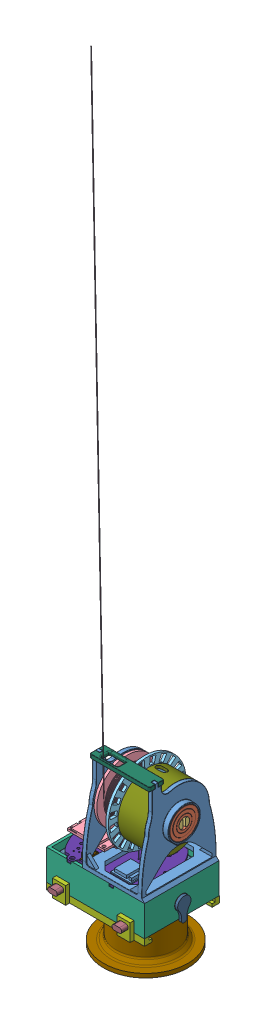
SolidWorks assembly Assembly, configuration Default. Lengths in mm.
Overall size (85.35 593.17 76.41).
29 component instances, 23 part files, 50 mates.
Components (placement in the parent):
- Housing-1: Housing [Default] at (10.1517 -3.3403 -3.0876) size (55.02 71.75 56)
- 608 bearing-1: 608 bearing [Default] at (31.6517 33.1597 24.9124) size (7 22 22)
- 608 bearing-2: 608 bearing [Default] at (-14.3483 33.1597 24.9124) size (7 22 22)
- Axel-1: Axel [Default] at (-5.3483 33.1597 24.9124) size (53 5.9 7.9)
- Spindle Encoder-1: Spindle Encoder [Default] at (-9.8483 33.1597 24.9124) x (0 -0.002146 0.999998) z (1 0 0) size (49.41 522.62 53)
- Spindle Housing-1: Spindle Housing [Default] at (7.1517 33.1597 24.9124) x (0 -0.924225 -0.381849) z (-1 0 0) size (58.5 58.5 53)
- Battery compartment-1: Battery compartment [Default] at (-4.0483 -29.3403 24.9124) x (0 0 1) z (-1 0 0) size (56 23 74)
- Compartment Bottom-1: Compartment Bottom [Default] at (-4.0483 -29.6403 24.6124) x (0 0 1) z (-1 0 0) size (62.6 12.9 74)
- Pillar-1: Pillar [Default] at (5.7517 -29.9403 24.6124) x (0 0 1) z (1 0 0) size (49.4 4 44.7)
- Pillar Base-1: Pillar Base [Default] at (5.7517 -57.3403 24.6124) x (0 0 -1) z (1 0 0) size (63.5 28.4 63.5)
- Pillar Lock-2: Pillar Lock [Default] at (30.5517 -19.3403 24.9124) x (0 0 -1) z (1 0 0) size (10 17.3 2)
- Pillar Lock Flange-2: Pillar Lock Flange [Default] at (30.9517 -19.3403 24.9124) x (0 -0.052142 0.99864) z (1 0 0) size (14 14 4.2)
- Piller Balance-1: Piller Balance [Default] at (-4.0483 -29.6403 24.6124) x (0 0 1) z (-1 0 0) size (51.4 4.63 48.65)
- Dowel-1: Dowel [Default] at (20.2517 -25.3403 50.3124) x (0 0 1) z (-1 0 0) size (10.6 3.7 7)
- Dowel-2: Dowel [Default] at (-28.3483 -25.3403 -1.0876) x (0 0 -1) z (1 0 0) size (10.6 3.7 7)
- Dowel-3: Dowel [Default] at (20.2517 -25.3403 -1.0876) x (0 0 -1) z (1 0 0) size (10.6 3.7 7)
- Dowel-4: Dowel [Default] at (-28.3483 -25.3403 50.3124) x (0 0 1) z (-1 0 0) size (10.6 3.7 7)
- Battery Case-1: Battery Case [Default] at (-4.0483 -27.3103 24.9124) x (0 0 -1) z (1 0 0) size (50 18 66)
- String Guard-1: String Guard [Default] at (-10.8483 62.4097 42.6624) size (45 3 11)
- Spring Mount Thin-1: Spring Mount Thin [Default] at (8.1517 33.1597 24.9124) size (20 46 46)
- PCB_Final-1: PCB_Final [Default] at (-8.0878 -10.7225 17.4115) x (0 0 -1) z (0 1 0) size (56.29 65.69 17.53)
  - JDL_PCB_From_Eagle-1: JDL_PCB_From_Eagle [Default] at (-7.6824 -3.0353 2.7693) size (56.29 65.69 1.61)
  - JDL_95C06F3GWT_TactSwitch-1: JDL_95C06F3GWT_TactSwitch [Default] at (-26.1821 9.2553 4.3822) x (-1 0 0) z (0 1 0) size (9.93 10.41 6.35)
  - JDL_95C06F3GWT_TactSwitch-2: JDL_95C06F3GWT_TactSwitch [Default] at (11.4099 9.2553 4.3822) x (-1 0 0) z (0 1 0) size (9.93 10.41 6.35)
  - JDL_RFDuino-1: JDL_RFDuino [Default] at (-20.5361 -15.9626 4.3822) x (1 0 0) z (0 -1 0) size (15.24 2.97 15.24)
  - JDL_JST_Female-1: JDL_JST_Female [Default] at (-11.5107 14.455 -0.5307) x (0 -1 0) z (1 0 0) size (7.9 5.5 7.6)
  - JDL_Inductor-1: JDL_Inductor [Default] at (-5.5489 20.3469 4.3822) x (1 0 0) z (0 -1 0) size (5.3 4.5 5.8)
  - OLED_NoOffset-1: OLED_NoOffset [Default] at (-7.7274 16.7735 9.2082) x (1 0 0) z (0 -1 0) size (28 12 28)
- Emitter_Detector-1: Emitter_Detector [Default] at (2.3717 -5.3603 24.9218) x (0 0 -1) z (1 0 0) size (7.82 15.5 11.48)
Mates (geometry in assembly coordinates):
- Concentric1: concentric anti-aligned: cylinder of Housing-1 through (-13.8483 33.1597 24.9124) axis (1 0 0) radius 11.15; cylinder of 608 bearing-1 through (31.1088 33.1597 24.9124) axis (-1 0 0) radius 11
- Coincident1: coincident aligned: plane of Housing-1 through (28.1517 -1.3403 52.9124) normal (-1 0 0); plane of 608 bearing-1 through (28.1517 28.9557 24.9124) normal (-1 0 0)
- Concentric2: concentric anti-aligned: cylinder of Housing-1 through (-13.8483 33.1597 24.9124) axis (1 0 0) radius 11.15; cylinder of 608 bearing-2 through (-14.8912 33.1597 24.9124) axis (-1 0 0) radius 11
- Coincident2: coincident aligned: plane of Housing-1 through (-10.8483 -1.3403 52.9124) normal (1 0 0); plane of 608 bearing-2 through (-10.8483 28.9557 24.9124) normal (1 0 0)
- Coincident3: coincident aligned: plane of 608 bearing-1 through (35.1517 28.9557 24.9124) normal (1 0 0); plane of Axel-1 through (35.1517 33.1597 24.9124) normal (1 0 0)
- Coincident5: coincident anti-aligned: plane of Spindle Encoder-1 through (5.1517 20.5273 24.8853) normal (1 0 0); plane of Spindle Housing-1 through (5.1517 33.1597 24.9124) normal (-1 0 0)
- Coincident43: coincident aligned: plane of Battery compartment-1 through (33.1517 -16.3403 52.9124) normal (1 0 0); plane of Compartment Bottom-1 through (33.1517 -31.9403 52.6124) normal (1 0 0)
- Parallel2: parallel anti-aligned: plane of Compartment Bottom-1 through (-15.2483 -61.6629 24.6124) normal (1 0 0); plane of Pillar-1 through (-14.2483 -31.9403 39.1069) normal (-1 0 0)
- Concentric18: concentric aligned: cylinder of Compartment Bottom-1 through (5.7517 -31.9403 24.6124) axis (0 1 0) radius 25; cylinder of Pillar-1 through (5.7517 -31.9403 24.6124) axis (0 1 0) radius 24.7
- Coincident54: coincident anti-aligned: plane of Pillar-1 through (5.7517 -31.9403 24.6124) normal (0 -1 0); plane of Pillar Base-1 through (5.7517 -31.9403 37.3124) normal (0 1 0)
- Concentric20: concentric aligned: cylinder of Pillar-1 through (5.7517 -31.9403 24.6124) axis (0 1 0) radius 24.7; cylinder of Pillar Base-1 through (5.7517 -31.9403 24.6124) axis (0 1 0) radius 22.2
- Coincident56: coincident anti-aligned: plane of Battery compartment-1 through (-40.8483 -29.3403 52.9124) normal (0 -1 0); plane of Compartment Bottom-1 through (5.7517 -29.3403 24.6124) normal (0 1 0)
- Concentric21: concentric anti-aligned: circle of 608 bearing-1; circle of Axel-1
- Concentric22: concentric anti-aligned: circle of Axel-1; circle of Spindle Housing-1
- Coincident67: coincident anti-aligned: plane of Compartment Bottom-1 through (5.7517 -31.9403 24.6124) normal (0 1 0); plane of Pillar-1 through (5.7517 -31.9403 24.6124) normal (0 -1 0)
- Coincident73: coincident anti-aligned: plane of Compartment Bottom-1 through (-17.2483 -31.9403 38.7546) normal (-1 0 0); plane of Piller Balance-1 through (-17.2483 -29.3103 38.7546) normal (1 0 0)
- Distance13: distance = 0.03 mm anti-aligned: plane of Piller Balance-1 through (5.7517 -29.3103 24.6124) normal (0 -1 0); plane of Compartment Bottom-1 through (5.7517 -29.3403 24.6124) normal (0 1 0)
- Concentric23: concentric anti-aligned: cylinder of Compartment Bottom-1 through (5.7517 -31.9403 24.6124) axis (0 1 0) radius 25; cylinder of Piller Balance-1 through (5.7517 -29.3103 24.6124) axis (0 -1 0) radius 27
- Coincident74: coincident anti-aligned: plane of Compartment Bottom-1 through (-33.3483 -21.3403 55.9124) normal (0 0 1); plane of Dowel-4 through (-24.8483 -23.4903 55.9124) normal (0 0 -1)
- Concentric24: concentric aligned: cylinder of Battery compartment-1 through (-28.3483 -25.3403 66.9124) axis (0 0 -1) radius 2.65; cylinder of Dowel-4 through (-28.3483 -25.3403 55.9124) axis (0 0 -1) radius 2.35
- Coincident75: coincident anti-aligned: plane of Compartment Bottom-1 through (15.2517 -21.3403 55.9124) normal (0 0 1); plane of Dowel-1 through (23.7517 -23.4903 55.9124) normal (0 0 -1)
- Concentric25: concentric aligned: cylinder of Battery compartment-1 through (20.2517 -25.3403 66.9124) axis (0 0 -1) radius 2.65; cylinder of Dowel-1 through (20.2517 -25.3403 55.9124) axis (0 0 -1) radius 2.35
- Coincident76: coincident anti-aligned: plane of Compartment Bottom-1 through (-33.3483 -21.3403 -6.6876) normal (0 0 -1); plane of Dowel-2 through (-31.8483 -23.4903 -6.6876) normal (0 0 1)
- Concentric26: concentric anti-aligned: cylinder of Battery compartment-1 through (-28.3483 -25.3403 66.9124) axis (0 0 -1) radius 2.65; cylinder of Dowel-2 through (-28.3483 -25.3403 -6.6876) axis (0 0 1) radius 2.35
- Coincident77: coincident anti-aligned: plane of Compartment Bottom-1 through (15.2517 -21.3403 -6.6876) normal (0 0 -1); plane of Dowel-3 through (16.7517 -23.4903 -6.6876) normal (0 0 1)
- Concentric27: concentric anti-aligned: cylinder of Battery compartment-1 through (20.2517 -25.3403 66.9124) axis (0 0 -1) radius 2.65; cylinder of Dowel-3 through (20.2517 -25.3403 -6.6876) axis (0 0 1) radius 2.35
- Coincident100: coincident anti-aligned: plane of Piller Balance-1 through (5.7517 -27.3103 24.6124) normal (0 1 0); plane of Battery Case-1 through (-37.0483 -27.3103 -0.0876) normal (0 -1 0)
- Distance24: distance = 1 mm anti-aligned: plane of Battery Case-1 through (-4.0483 -9.3103 -0.0876) normal (0 0 -1); plane of Battery compartment-1 through (31.1517 -16.3403 -1.0876) normal (0 0 1)
- Coincident102: coincident anti-aligned: plane of Battery compartment-1 through (-4.0483 -16.3403 52.9124) normal (0 0 1); plane of Compartment Bottom-1 through (-33.3483 -21.3403 52.9124) normal (0 0 -1)
- Coincident103: coincident anti-aligned: plane of Battery compartment-1 through (33.1517 -16.3403 52.9124) normal (1 0 0); plane of Pillar Lock-2 through (33.1517 -28.3403 36.9124) normal (-1 0 0)
- Coincident104: coincident anti-aligned: plane of Pillar Lock-2 through (33.1517 -28.3403 36.9124) normal (-1 0 0); plane of Pillar Lock Flange-2 through (33.1517 -19.3403 24.9124) normal (1 0 0)
- Concentric30: concentric anti-aligned: cylinder of Pillar Lock-2 through (35.1517 -19.3403 24.9124) axis (-1 0 0) radius 5; circle of Pillar Lock Flange-2
- Coincident105: coincident anti-aligned: plane of Pillar Lock Flange-2 through (28.9517 -19.3403 24.9124) normal (-1 0 0); plane of Battery Case-1 through (28.9517 -9.3103 49.9124) normal (1 0 0)
- Coincident107: coincident anti-aligned: plane of Housing-1 through (31.1517 -6.3403 52.9124) normal (0 -1 0); plane of Battery compartment-1 through (-40.8483 -6.3403 52.9124) normal (0 1 0)
- Concentric31: concentric aligned: cylinder of Battery compartment-1 through (33.1527 -19.3403 24.9124) axis (-1 0 0) radius 5.3; cylinder of Pillar Lock Flange-2 through (33.1517 -19.3403 24.9124) axis (-1 0 0) radius 4.7
- Distance25: distance = 2 mm aligned: plane of Housing-1 through (31.1517 -1.3403 52.9124) normal (1 0 0); plane of Battery compartment-1 through (33.1517 -16.3403 52.9124) normal (1 0 0)
- Coincident114: coincident aligned: plane of Housing-1 through (26.1517 -1.3403 52.9124) normal (0 0 1); plane of Battery compartment-1 through (-4.0483 -16.3403 52.9124) normal (0 0 1)
- Distance30: distance = 0.3 mm anti-aligned: plane of Housing-1 through (-10.8483 -1.3403 52.9124) normal (1 0 0); plane of String Guard-1 through (-10.5483 65.4097 42.9624) normal (-1 0 0)
- Distance29: distance = 0.3 mm anti-aligned: plane of Housing-1 through (17.9596 62.4097 40.6624) normal (0 0 -1); plane of String Guard-1 through (-10.5483 65.4097 40.3624) normal (0 0 1)
- Coincident118: coincident aligned: plane of Housing-1 through (59.9596 65.4097 40.6624) normal (0 1 0); plane of String Guard-1 through (30.1517 65.4097 37.1624) normal (0 1 0)
- Distance31: distance = 1 mm anti-aligned: plane of Spindle Encoder-1 through (-9.8483 20.5273 24.8853) normal (-1 0 0); plane of Housing-1 through (-10.8483 -1.3403 52.9124) normal (1 0 0)
- Coincident127: coincident anti-aligned: plane of Housing-1 through (28.1517 -1.3403 52.9124) normal (-1 0 0); plane of Spring Mount Thin-1 through (28.1517 33.1597 24.9124) normal (1 0 0)
- Concentric32: concentric aligned: cylinder of Spindle Encoder-1 through (-9.8483 33.1597 24.9124) axis (-1 0 0) radius 16.75; cylinder of Spring Mount Thin-1 through (28.1517 33.1597 24.9124) axis (-1 0 0) radius 23
- Concentric33: concentric anti-aligned: circle of Housing-1; circle of Spindle Encoder-1
- Parallel3: parallel aligned: plane of Battery compartment-1 through (-40.8483 -16.3403 -3.0876) normal (-1 0 0); plane of PCB_Final-1/JDL_PCB_From_Eagle-1 through (11.9388 -6.3403 25.4046) normal (-1 0 0)
- Parallel4: parallel aligned: plane of PCB_Final-1/JDL_RFDuino-1 through (1.5756 -3.3685 44.1452) normal (-1 0 0); plane of Emitter_Detector-1 through (0.8667 8.2397 26.8568) normal (-1 0 0)
- Distance32: distance = 15.2822 mm anti-aligned: plane of Emitter_Detector-1 through (12.3517 9.2397 21.6068) normal (0 0 -1); plane of PCB_Final-1/JDL_PCB_From_Eagle-1 through (69.4946 -6.3403 6.3246) normal (0 0 1)
- Distance33: distance = 0.7089 mm aligned: plane of Emitter_Detector-1 through (0.8667 8.2397 26.8568) normal (-1 0 0); plane of PCB_Final-1/JDL_RFDuino-1 through (1.5756 -3.3685 44.1452) normal (-1 0 0)
- Distance34: distance = 3 mm anti-aligned: plane of Emitter_Detector-1 through (10.1517 9.2397 24.6068) normal (-1 0 0); plane of Spindle Housing-1 through (7.1517 33.1597 24.9124) normal (1 0 0)
- Coincident136: coincident aligned: plane of Battery compartment-1 through (-40.8483 -6.3403 52.9124) normal (0 1 0); plane of PCB_Final-1/JDL_PCB_From_Eagle-1 through (69.4946 -6.3403 25.4046) normal (0 1 0)
